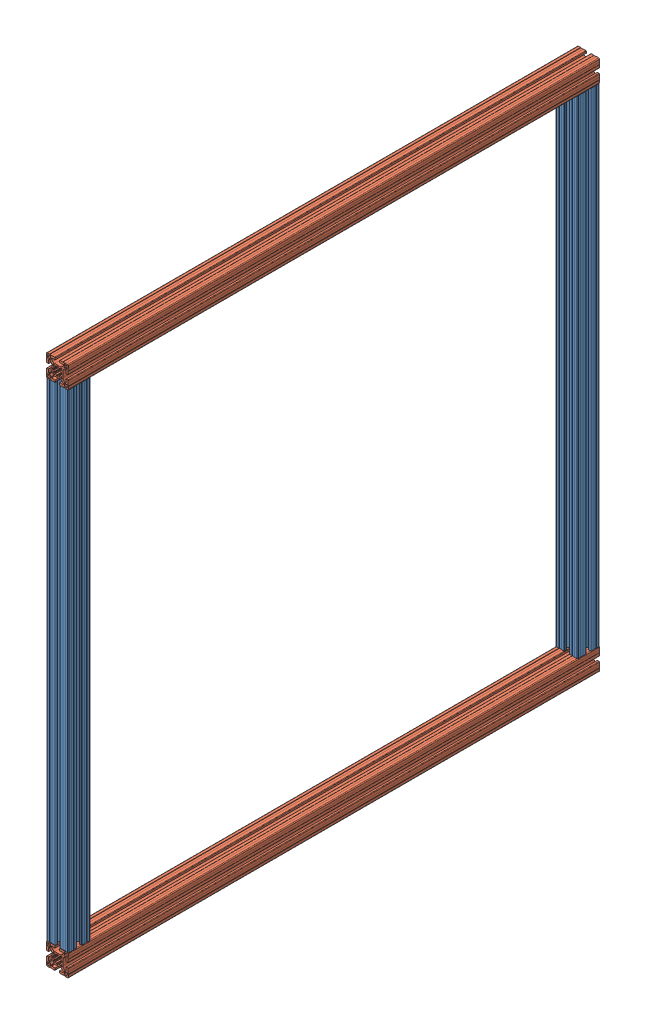
SolidWorks assembly Porta_Mod_Clean, configuration Valor predeterminado. Lengths in mm.
Overall size (40 970 970).
4 component instances, 2 part files, 3 mates.
Components (placement in the parent):
- Perfil_Alum_4x4x89-1: Perfil_Alum_4x4x89 [Valor predeterminado] at (-16.2893 394.6537 1371.7408) x (1 0 0) z (0 -1 0) size (40 40 890)
- Perfil_Alum_4x4x97-1: Perfil_Alum_4x4x97 [Valor predeterminado] at (-16.2893 -70.3463 906.7408) size (40 40 970)
- Perfil_Alum_4x4x97-2: Perfil_Alum_4x4x97 [Valor predeterminado] at (-16.2893 859.6537 906.7408) size (40 40 970)
- Perfil_Alum_4x4x89-2: Perfil_Alum_4x4x89 [Valor predeterminado] at (-16.2893 394.6537 441.7408) x (1 0 0) z (0 -1 0) size (40 40 890)
Mates (geometry in assembly coordinates):
- Coincidente1: coincident: point of Perfil_Alum_4x4x97-1; unknown of Perfil_Alum_4x4x89-2
- Coincidente2: coincident: unknown of Perfil_Alum_4x4x89-1; unknown of Perfil_Alum_4x4x97-1
- Coincidente3: coincident: unknown of Perfil_Alum_4x4x89-1; unknown of Perfil_Alum_4x4x97-2
